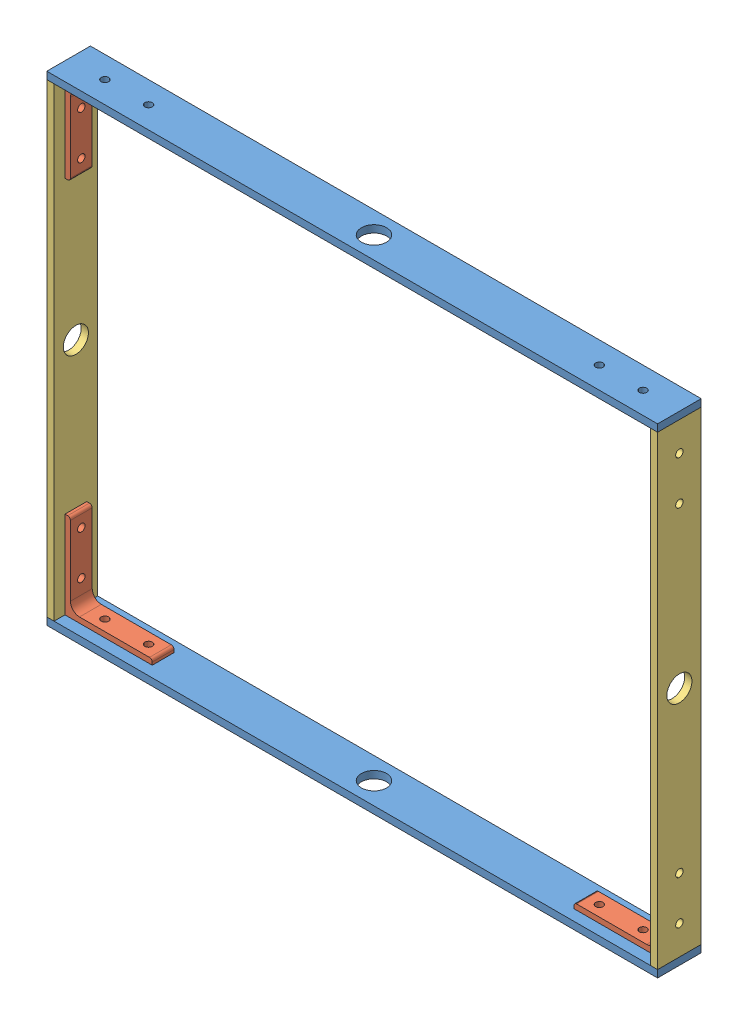
SolidWorks assembly Inner Ring, configuration Default. Lengths in mm.
Overall size (533.4 419.1 38.1).
8 component instances, 3 part files, 16 mates.
Components (placement in the parent):
- InR_L_22mm-1: InR_L_22mm [Default] at (-174.5145 -430.4576 382.3784) size (533.4 6.35 38.1)
- Stand_Bracket_3in-1: Stand_Bracket_3in [8982K254] at (47.7355 -386.0076 382.3784) size (76.2 76.2 19.05)
- Stand_Bracket_3in-2: Stand_Bracket_3in [8982K254] at (-396.7645 -386.0076 382.3784) x (-1 0 0) z (0 0 -1) size (76.2 76.2 19.05)
- InR_L_22mm-2: InR_L_22mm [Default] at (-174.5145 -11.3576 382.3784) x (-1 0 0) z (0 0 1) size (533.4 6.35 38.1)
- Stand_Bracket_3in-3: Stand_Bracket_3in [8982K254] at (47.7355 -55.8076 382.3784) x (1 0 0) z (0 0 -1) size (76.2 76.2 19.05)
- Stand_Bracket_3in-4: Stand_Bracket_3in [8982K254] at (-396.7645 -55.8076 382.3784) x (-1 0 0) z (0 0 1) size (76.2 76.2 19.05)
- InR_S_22mm-1: InR_S_22mm [Default] at (-441.2145 -220.9076 382.3784) x (0 -1 0) z (0 0 1) size (406.4 6.35 38.1)
- InR_S_22mm-2: InR_S_22mm [Default] at (85.8355 -220.9076 382.3784) x (0 -1 0) z (0 0 1) size (406.4 6.35 38.1)
Mates (geometry in assembly coordinates):
- Coincident1: coincident aligned: circle of InR_L_22mm-1; circle of Stand_Bracket_3in-1
- Coincident2: coincident aligned: circle of InR_L_22mm-1; circle of Stand_Bracket_3in-1
- Coincident3: coincident aligned: circle of InR_L_22mm-1; circle of Stand_Bracket_3in-2
- Coincident4: coincident aligned: circle of InR_L_22mm-1; circle of Stand_Bracket_3in-2
- Coincident5: coincident aligned: circle of InR_L_22mm-2; circle of Stand_Bracket_3in-3
- Coincident6: coincident aligned: circle of InR_L_22mm-2; circle of Stand_Bracket_3in-4
- Coincident7: coincident aligned: circle of InR_L_22mm-2; circle of Stand_Bracket_3in-4
- Coincident8: coincident aligned: circle of InR_L_22mm-2; circle of Stand_Bracket_3in-3
- Coincident11: coincident aligned: circle of Stand_Bracket_3in-2; circle of InR_S_22mm-1
- Coincident12: coincident aligned: circle of Stand_Bracket_3in-2; circle of InR_S_22mm-1
- Coincident13: coincident aligned: circle of Stand_Bracket_3in-4; circle of InR_S_22mm-1
- Coincident14: coincident aligned: circle of Stand_Bracket_3in-4; circle of InR_S_22mm-1
- Coincident15: coincident anti-aligned: circle of Stand_Bracket_3in-3; circle of InR_S_22mm-2
- Coincident16: coincident anti-aligned: circle of Stand_Bracket_3in-3; circle of InR_S_22mm-2
- Coincident17: coincident anti-aligned: circle of Stand_Bracket_3in-1; circle of InR_S_22mm-2
- Coincident18: coincident anti-aligned: circle of Stand_Bracket_3in-1; circle of InR_S_22mm-2
